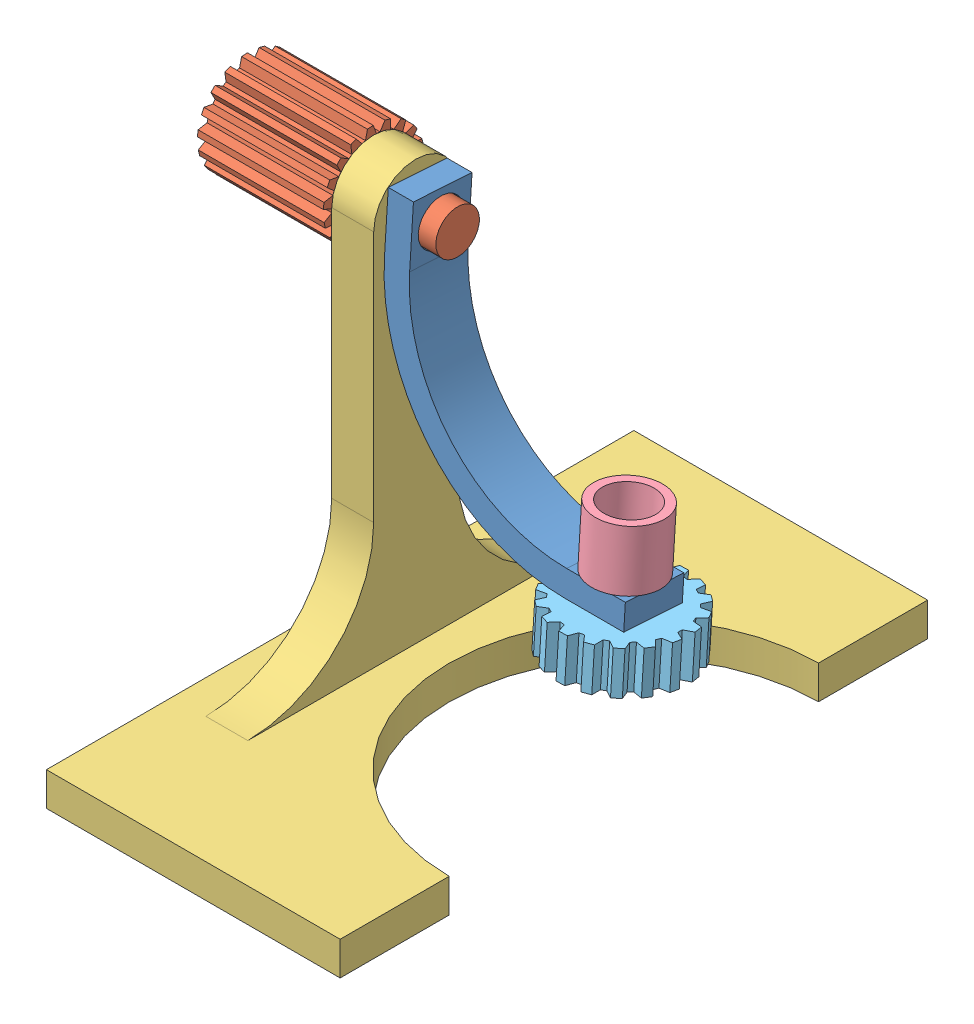
SolidWorks assembly stage, configuration Default. Lengths in mm.
Overall size (54.57 55.37 70).
5 component instances, 5 part files, 7 mates.
Components (placement in the parent):
- stage_arm-1: stage_arm [Default] at (12.8849 36.6207 16.3231) x (1 0 0) z (0 0.064772 0.9979) size (30 30 7)
- stage_axis-1: stage_axis [Default] at (-30.1151 40.3401 19.589) x (0 -0.064772 -0.9979) z (1 0 0) size (12.02 11.99 25)
- stage_base-1: stage_base [Default] at (-1.6151 -8.6599 19.589) x (0 0 1) z (0 1 0) size (70 35 54)
- stage_mount-1: stage_mount [Default] at (16.3849 16.8894 21.1112) x (1 0 0) z (0 0.9979 -0.064772) size (8 8 7)
- stage_pin-1: stage_pin [Default] at (16.3849 8.9062 21.6293) x (0.078769 0.064571 0.9948) z (0 0.9979 -0.064772) size (15.03 15 10)
Mates (geometry in assembly coordinates):
- Concentric1: concentric: cylinder of stage_axis-1 through (-5.1151 40.3401 19.589) axis (-1 0 0) radius 2.6; cylinder of stage_base-1 through (-45.1151 40.3401 19.589) axis (1 0 0) radius 2.7
- Coincident1: coincident: plane of stage_axis-1 through (-15.1151 40.3401 19.589) normal (1 0 0); plane of stage_base-1 through (-15.1151 45.3401 24.589) normal (-1 0 0)
- Concentric2: concentric: circle of stage_arm-1; cylinder of stage_axis-1 through (-5.1151 40.3401 19.589) axis (-1 0 0) radius 2.6
- Coincident4: coincident: plane of stage_arm-1 through (-10.1151 37.0741 23.3084) normal (-1 0 0); plane of stage_base-1 through (-10.1151 45.3401 24.589) normal (1 0 0)
- Coincident5: coincident: plane of stage_arm-1 through (12.8849 14.1224 24.7981) normal (0 -0.9979 0.064772); plane of stage_pin-1 through (16.3849 13.8957 21.3055) normal (0 0.9979 -0.064772)
- Concentric4: concentric: cylinder of stage_mount-1 through (16.3849 23.8747 20.6578) axis (0 -0.9979 0.064772) radius 1.9; cylinder of stage_pin-1 through (16.3849 18.8852 20.9816) axis (0 -0.9979 0.064772) radius 1.9
- Coincident6: coincident: circle of stage_mount-1; circle of stage_pin-1
